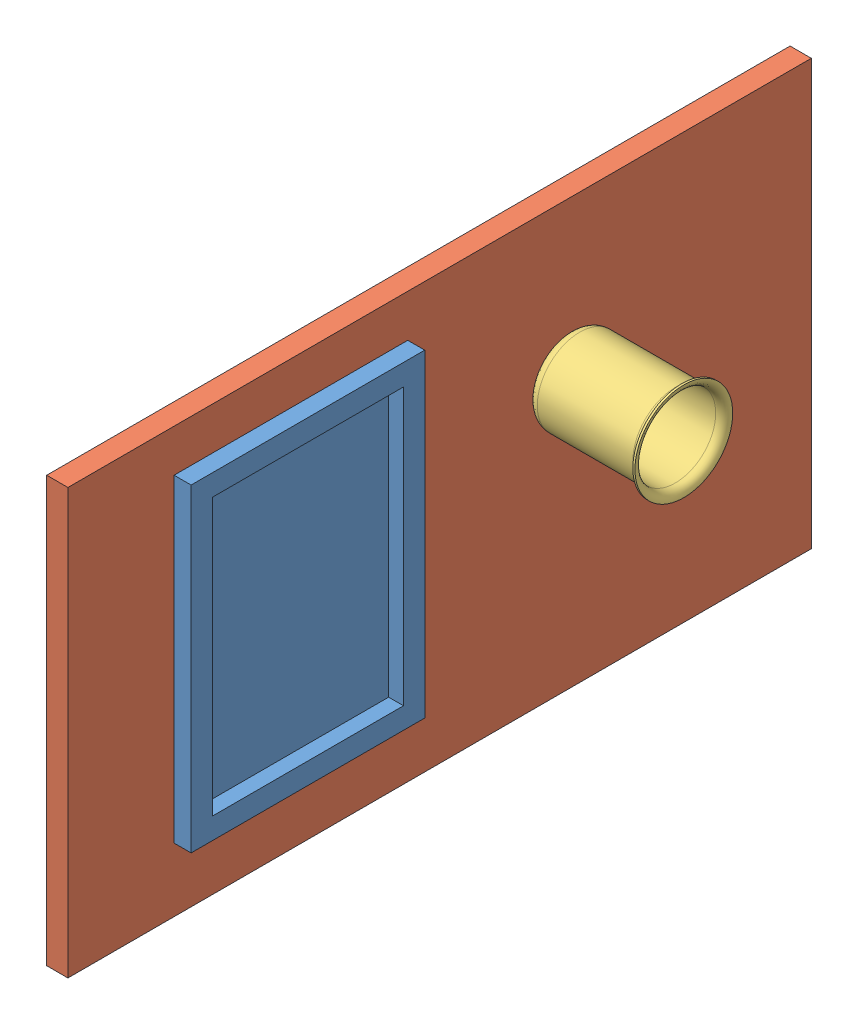
SolidWorks assembly Sestava1, configuration Default. Lengths in mm.
Overall size (69 200 350).
3 component instances, 3 part files, 5 mates.
Components (placement in the parent):
- Podlozka-1: Podlozka [Výchozí] at (10 5 70) x (0 0 1) z (0 1 0) size (110 8 150)
- Police-1: Police [Výchozí] at origin size (15 200 350)
- SKLENIČKA-1: SKLENIČKA [Výchozí] at (10 27.8511 -60.9737) x (0 -1 0) z (0 0 1) size (46 54 46)
Mates (geometry in assembly coordinates):
- Sjednocená1: coordinate: point of Police-1; point of assembly
- Sjednocená2: coincident: plane of Podlozka-1 through (10 80 15) normal (-1 0 0); plane of Police-1 through (10 -100 -175) normal (1 0 0)
- Vzdálenost1: distance = 50 mm: plane of Podlozka-1 through (18 -70 125) normal (0 0 1); plane of Police-1 through (10 100 175) normal (0 0 1)
- Vzdálenost2: distance = 30 mm: plane of Podlozka-1 through (18 -70 15) normal (0 -1 0); plane of Police-1 through (10 -100 175) normal (0 -1 0)
- Sjednocená5: coincident: plane of Police-1 through (10 -100 -175) normal (1 0 0); plane of SKLENIČKA-1 through (10 27.8511 -60.9737) normal (-1 0 0)
